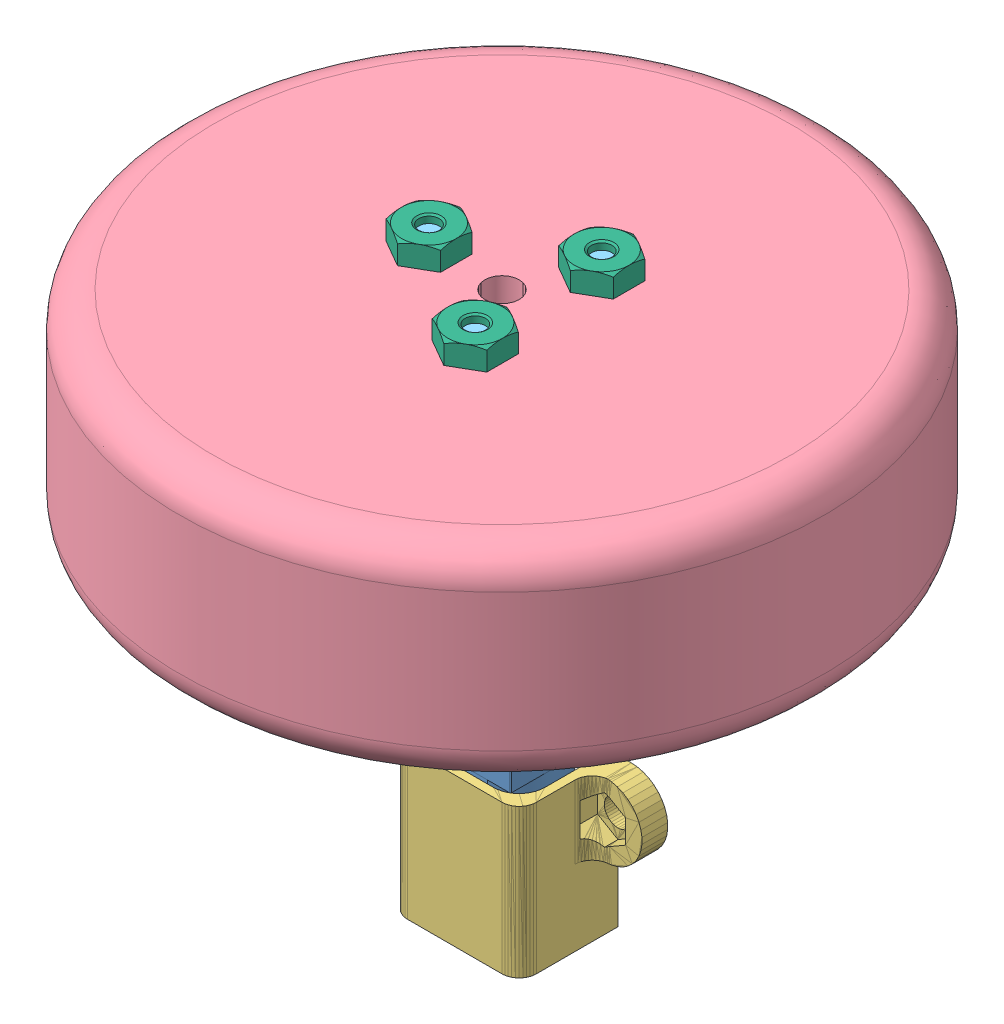
SolidWorks assembly motor_assembly, configuration Default. Lengths in mm.
Overall size (102.45 66.46 102.45).
10 component instances, 6 part files, 13 mates.
Components (placement in the parent):
- 01_micro_metal_gearmotor-1: 01_micro_metal_gearmotor [По умолчанию] at (7.6392 6.8545 37.8366) size (12.1 35.27 10.12)
- 02_motor_hub-1: 02_motor_hub [Default] at (7.6392 33.6245 37.8366) x (0 0 -1) z (1 0 0) size (23 8 23)
- 03_motor_mount-1: 03_motor_mount [Default] at (-5.1608 -3.6518 104.3827) x (0 0.08713 -0.996197) z (1 0 0) size (12.96 18.24 26.57)
- 04_wheel-1: 04_wheel [Default] at (7.6392 41.6245 37.8366) x (0.866025 0 -0.5) z (0 1 0) size (75 75 24)
- pan cross head_ai-1: pan cross head_ai [CR-PHMS 0.112-40x1.125x1.125-N] at (-0.8608 36.5925 37.8366) x (0 1 0) z (0 0 1) size (30.57 5.56 5.56)
- pan cross head_ai-2: pan cross head_ai [CR-PHMS 0.112-40x1.125x1.125-N] at (11.8892 36.5925 30.4754) x (0 1 0) z (-0.866025 0 -0.5) size (30.57 5.56 5.56)
- pan cross head_ai-3: pan cross head_ai [CR-PHMS 0.112-40x1.125x1.125-N] at (11.8892 36.5925 45.1978) x (0 1 0) z (0.866025 0 -0.5) size (30.57 5.56 5.56)
- machine screw nut hex_ai-1: machine screw nut hex_ai [MSHXNUT 0.112-48-S-N] at (-0.8608 68.1137 37.8366) x (1 0 0) z (0 1 0) size (6.35 7.33 2.49)
- machine screw nut hex_ai-2: machine screw nut hex_ai [MSHXNUT 0.112-48-S-N] at (11.8892 68.1137 45.1978) x (-0.5 0 -0.866025) z (0 1 0) size (6.35 7.33 2.49)
- machine screw nut hex_ai-3: machine screw nut hex_ai [MSHXNUT 0.112-48-S-N] at (11.8892 68.1137 30.4754) x (-0.5 0 0.866025) z (0 1 0) size (6.35 7.33 2.49)
Mates (geometry in assembly coordinates):
- Concentric1: concentric aligned: cylinder of 01_micro_metal_gearmotor-1 through (7.6392 38.6245 37.8366) axis (0 -1 0) radius 1.5; cylinder of 02_motor_hub-1 through (7.6392 38.6245 37.8366) axis (0 -1 0) radius 1.5
- Parallel1: parallel anti-aligned: plane of 01_micro_metal_gearmotor-1 through (8.6392 38.6245 36.7185) normal (1 0 0); plane of 02_motor_hub-1 through (8.6644 38.6245 38.9316) normal (-1 0 0)
- Coincident2: coincident anti-aligned: plane of 01_micro_metal_gearmotor-1 through (7.6392 38.6245 37.8366) normal (0 1 0); plane of 02_motor_hub-1 through (7.6392 38.6245 37.8366) normal (0 -1 0)
- Coincident3: coincident anti-aligned: plane of 01_micro_metal_gearmotor-1 through (4.3226 20.3545 42.8366) normal (0 0 1); plane of 03_motor_mount-1 through (-5.1608 -3.6518 42.8366) normal (0 0 -1)
- Coincident4: coincident anti-aligned: plane of 01_micro_metal_gearmotor-1 through (1.6392 29.3545 32.8383) normal (-1 0 0); plane of 03_motor_mount-1 through (1.6392 -3.6518 104.3827) normal (1 0 0)
- Parallel2: parallel anti-aligned: plane of 01_micro_metal_gearmotor-1 through (13.6392 29.3545 32.8383) normal (1 0 0); plane of 03_motor_mount-1 through (14.6392 -3.6518 104.3827) normal (-1 0 0)
- Coincident8: coincident anti-aligned: plane of 02_motor_hub-1 through (7.6392 41.6245 37.8366) normal (0 1 0); plane of 04_wheel-1 through (7.6392 41.6245 37.8366) normal (0 -1 0)
- Coincident10: coincident anti-aligned: circle of 02_motor_hub-1; circle of 04_wheel-1
- Concentric2: concentric anti-aligned: cylinder of 02_motor_hub-1 through (-0.8608 41.6245 37.8366) axis (0 -1 0) radius 1.5; cylinder of 04_wheel-1 through (-0.8608 41.6245 37.8366) axis (0 1 0) radius 1.5
- Concentric51: concentric aligned: cylinder of 02_motor_hub-1 through (-0.8608 41.6245 37.8366) axis (0 -1 0) radius 1.5; cylinder of pan cross head_ai-1 through (-0.8608 11.1925 37.8366) axis (0 -1 0) radius 1.4224
- Coincident131: coincident anti-aligned: plane of 02_motor_hub-1 through (7.6392 38.6245 37.8366) normal (0 -1 0); plane of pan cross head_ai-1 through (-2.2832 38.6245 37.8366) normal (0 1 0)
- Concentric6: concentric anti-aligned: cylinder of pan cross head_ai-1 through (-0.8608 11.1925 37.8366) axis (0 -1 0) radius 1.4224; cylinder of machine screw nut hex_ai-1 through (-0.8608 43.0762 37.8366) axis (0 1 0) radius 1.4224
- Coincident14: coincident anti-aligned: plane of 04_wheel-1 through (7.6392 65.6245 37.8366) normal (0 1 0); plane of machine screw nut hex_ai-1 through (-7.2108 65.6245 37.8366) normal (0 -1 0)
